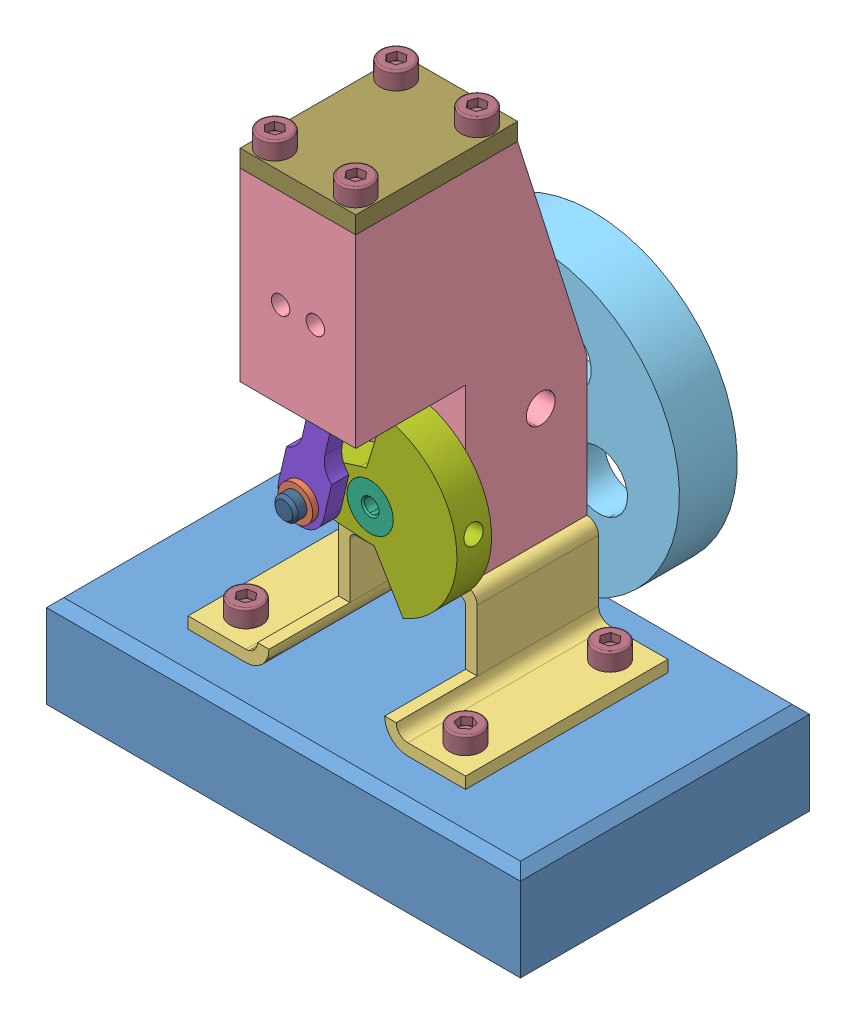
SolidWorks assembly airmotor, configuration Default. Lengths in mm.
Overall size (82 100.59 61).
20 component instances, 13 part files, 41 mates.
Components (placement in the parent):
- Part1-1: Part1 [Default] at (28.4885 33.8393 64.708) size (82 16 50)
- Part10-1: Part10 [Default] at (20.5462 75.4658 79.208) x (-1 0 0) z (0 -1 0) size (6 1 6)
- Part2-1: Part2 [Default] at (28.4885 33.5714 47.208) size (48 16.59 35)
- Part3-1: Part3 [Default] at (28.4885 66.4251 47.208) x (0 0 -1) z (1 0 0) size (40 62 20)
- Part4-1: Part4 [Default] at (28.4885 76.4251 46.208) x (0.91814 -0.396257 0) z (0.396257 0.91814 0) size (50 11 50)
- Part5-1: Part5 [Default] at (28.4885 76.4251 74.708) x (0 -1 0) z (1 0 0) size (8 46 8)
- Part6-1: Part6 [Default] at (28.4885 76.4251 71.708) x (0.11991 -0.992785 0) z (0 0 -1) size (28.91 27 6.5)
- Part7-1: Part7 [Default] at (22.9333 85.711 77.208) x (0.226922 0.973913 0) z (-0.973913 0.226922 0) size (42 3 8)
- Part8-1: Part8 [Default] at (28.4885 102.5527 77.208) x (-1 0 0) z (0 0 -1) size (14 15 14)
- Part9-1: Part9 [Default] at (19.7977 75.1346 75.208) x (0 0 -1) z (-0.40461 0.914489 0) size (13 4 4)
- Part11-1: Part11 [Default] at (28.4885 109.5527 83.958) x (-1 0 0) z (0 0 -1) size (3 3 13.5)
- Part12-1: Part12 [Default] at (28.4885 131.4251 73.208) x (0 0 1) z (1 0 0) size (28 3 20)
- socket head cap screw 4762_din-1: socket head cap screw 4762_din [EN ISO 4762 M3 x 6 - 6N] at (9.4885 54.8393 52.208) x (0 -1 0) z (-0.899893 0 0.43611) size (9 5.5 5.5)
- socket head cap screw 4762_din-2: socket head cap screw 4762_din [EN ISO 4762 M3 x 6 - 6N] at (9.4885 54.8393 77.208) x (0 -1 0) z (0.170896 0 0.985289) size (9 5.5 5.5)
- socket head cap screw 4762_din-3: socket head cap screw 4762_din [EN ISO 4762 M3 x 6 - 6N] at (47.4885 54.8393 77.208) x (0 -1 0) z (0.616405 0 0.787429) size (9 5.5 5.5)
- socket head cap screw 4762_din-4: socket head cap screw 4762_din [EN ISO 4762 M3 x 6 - 6N] at (47.4885 54.8393 52.208) x (0 -1 0) z (0.946527 0 0.322625) size (9 5.5 5.5)
- socket head cap screw 4762_din-5: socket head cap screw 4762_din [EN ISO 4762 M3 x 6 - 6N] at (21.4885 134.4251 84.208) x (0 -1 0) z (0.287137 0 0.95789) size (9 5.5 5.5)
- socket head cap screw 4762_din-6: socket head cap screw 4762_din [EN ISO 4762 M3 x 6 - 6N] at (35.4885 134.4251 63.208) x (0 -1 0) z (0.16771 0 0.985836) size (9 5.5 5.5)
- socket head cap screw 4762_din-7: socket head cap screw 4762_din [EN ISO 4762 M3 x 6 - 6N] at (35.4885 134.4251 84.208) x (0 -1 0) z (0.170795 0 0.985307) size (9 5.5 5.5)
- socket head cap screw 4762_din-8: socket head cap screw 4762_din [EN ISO 4762 M3 x 6 - 6N] at (21.4885 134.4251 63.208) x (0 -1 0) z (0.200162 0 0.979763) size (9 5.5 5.5)
Mates (geometry in assembly coordinates):
- Coincident1: coincident anti-aligned: plane of Part1-1 through (28.4885 49.8393 64.708) normal (0 1 0); plane of Part2-1 through (28.4885 49.8393 82.208) normal (0 -1 0)
- Concentric1: concentric aligned: cylinder of Part1-1 through (47.4885 49.8393 52.208) axis (0 1 0) radius 1.65; cylinder of Part2-1 through (47.4885 49.8393 52.208) axis (0 1 0) radius 2
- Concentric2: concentric aligned: cylinder of Part1-1 through (9.4885 49.8393 77.208) axis (0 1 0) radius 1.65; cylinder of Part2-1 through (9.4885 49.8393 77.208) axis (0 1 0) radius 2
- Coincident2: coincident anti-aligned: plane of Part2-1 through (28.4885 66.4251 68.208) normal (0 1 0); plane of Part3-1 through (38.4885 66.4251 47.208) normal (0 -1 0)
- Concentric3: concentric anti-aligned: cylinder of Part2-1 through (28.4885 49.8393 63.208) axis (0 1 0) radius 2; cylinder of Part3-1 through (28.4885 66.4251 63.208) axis (0 -1 0) radius 1.65
- Concentric4: concentric anti-aligned: cylinder of Part2-1 through (28.4885 49.8393 55.208) axis (0 1 0) radius 2; cylinder of Part3-1 through (28.4885 66.4251 55.208) axis (0 -1 0) radius 1.65
- Concentric5: concentric anti-aligned: cylinder of Part3-1 through (28.4885 77.4251 63.208) axis (0 1 0) radius 1; cylinder of Part5-1 through (28.4885 88.4251 63.208) axis (0 -1 0) radius 2
- Concentric6: concentric anti-aligned: cylinder of Part3-1 through (28.4885 76.4251 87.208) axis (0 0 -1) radius 4; cylinder of Part5-1 through (28.4885 76.4251 40.708) axis (0 0 1) radius 4
- Concentric7: concentric aligned: cylinder of Part4-1 through (28.4885 76.4251 36.208) axis (0 0 1) radius 4; cylinder of Part5-1 through (28.4885 76.4251 28.708) axis (0 0 1) radius 2
- Coincident3: coincident anti-aligned: plane of Part3-1 through (38.4885 90.4251 47.208) normal (0 0 -1); plane of Part4-1 through (28.4885 76.4251 47.208) normal (0 0 1)
- Concentric9: concentric anti-aligned: cylinder of Part8-1 through (28.4885 109.5527 84.208) axis (0 0 -1) radius 1.5; cylinder of Part11-1 through (28.4885 109.5527 70.458) axis (0 0 1) radius 1.5
- Concentric10: concentric aligned: cylinder of Part7-1 through (28.4885 109.5527 75.708) axis (0 0 1) radius 1.5; cylinder of Part11-1 through (28.4885 109.5527 70.458) axis (0 0 1) radius 1.5
- Concentric11: concentric anti-aligned: cylinder of Part6-1 through (20.5462 75.4658 68.708) axis (0 0 1) radius 2; cylinder of Part9-1 through (20.5462 75.4658 68.708) axis (0 0 -1) radius 2
- Concentric12: concentric anti-aligned: cylinder of Part10-1 through (20.5462 75.4658 78.708) axis (0 0 1) radius 1.9; cylinder of Part9-1 through (20.5462 75.4658 68.708) axis (0 0 -1) radius 1.6434
- Coincident4: coincident anti-aligned: plane of Part10-1 through (20.5462 75.4658 78.708) normal (0 0 -1); plane of Part9-1 through (19.0434 74.8009 78.708) normal (0 0 1)
- Concentric13: concentric anti-aligned: cylinder of Part7-1 through (20.5462 75.4658 75.708) axis (0 0 1) radius 2; cylinder of Part9-1 through (20.5462 75.4658 68.708) axis (0 0 -1) radius 2
- Concentric14: concentric aligned: cylinder of Part3-1 through (28.4885 66.4251 77.208) axis (0 1 0) radius 7; cylinder of Part8-1 through (28.4885 121.9198 77.208) axis (0 1 0) radius 7
- Width1: width anti-aligned: plane of Part11-1 through (28.4885 109.5527 70.458) normal (0 0 -1); plane of Part7-1 through (28.4885 109.5527 83.958) normal (0 0 1); plane of Part11-1 through (20.5462 75.4658 78.708) normal (0 0 1); plane of Part7-1 through (20.5462 75.4658 75.708) normal (0 0 -1)
- Concentric15: concentric aligned: cylinder of Part5-1 through (28.4885 76.4251 40.708) axis (0 0 1) radius 4; cylinder of Part6-1 through (28.4885 76.4251 68.208) axis (0 0 1) radius 4
- Coincident5: coincident aligned: plane of Part6-1 through (28.4885 76.4251 68.708) normal (0 0 -1); plane of Part9-1 through (20.5462 75.4658 68.708) normal (0 0 -1)
- Coincident6: coincident anti-aligned: plane of Part3-1 through (38.4885 66.4251 68.208) normal (0 0 1); plane of Part6-1 through (28.4885 76.4251 68.208) normal (0 0 -1)
- Coincident7: coincident anti-aligned: plane of Part10-1 through (20.5462 75.4658 78.708) normal (0 0 -1); plane of Part7-1 through (20.5462 75.4658 78.708) normal (0 0 1)
- Coincident9: coincident anti-aligned: plane of Part3-1 through (38.4885 128.4251 87.208) normal (0 1 0); plane of Part12-1 through (28.4885 128.4251 73.208) normal (0 -1 0)
- Coincident11: coincident aligned: plane of Part3-1 through (38.4885 96.4251 87.208) normal (0 0 1); plane of Part12-1 through (28.4885 128.4251 87.208) normal (0 0 1)
- Coincident12: coincident aligned: plane of Part3-1 through (18.4885 66.4251 47.208) normal (-1 0 0); plane of Part12-1 through (18.4885 128.4251 73.208) normal (-1 0 0)
- Concentric20: concentric aligned: cylinder of Part1-1 through (9.4885 49.8393 52.208) axis (0 1 0) radius 1.65; cylinder of socket head cap screw 4762_din-1 through (9.4885 86.5893 52.208) axis (0 1 0) radius 1.5
- Concentric21: concentric aligned: cylinder of Part1-1 through (9.4885 49.8393 77.208) axis (0 1 0) radius 1.65; cylinder of socket head cap screw 4762_din-2 through (9.4885 86.5893 77.208) axis (0 1 0) radius 1.5
- Concentric22: concentric aligned: cylinder of Part1-1 through (47.4885 49.8393 77.208) axis (0 1 0) radius 1.65; cylinder of socket head cap screw 4762_din-3 through (47.4885 86.5893 77.208) axis (0 1 0) radius 1.5
- Concentric23: concentric aligned: cylinder of Part1-1 through (47.4885 49.8393 52.208) axis (0 1 0) radius 1.65; cylinder of socket head cap screw 4762_din-4 through (47.4885 86.5893 52.208) axis (0 1 0) radius 1.5
- Coincident13: coincident anti-aligned: plane of Part2-1 through (28.4885 51.8393 82.208) normal (0 1 0); plane of socket head cap screw 4762_din-4 through (48.3757 51.8393 49.605) normal (0 -1 0)
- Coincident14: coincident anti-aligned: plane of Part2-1 through (28.4885 51.8393 82.208) normal (0 1 0); plane of socket head cap screw 4762_din-3 through (49.6539 51.8393 75.5129) normal (0 -1 0)
- Coincident15: coincident anti-aligned: plane of Part2-1 through (28.4885 51.8393 82.208) normal (0 1 0); plane of socket head cap screw 4762_din-2 through (12.198 51.8393 76.738) normal (0 -1 0)
- Coincident16: coincident anti-aligned: plane of Part2-1 through (28.4885 51.8393 82.208) normal (0 1 0); plane of socket head cap screw 4762_din-1 through (10.6878 51.8393 54.6827) normal (0 -1 0)
- Concentric24: concentric: cylinder of Part12-1 through (35.4885 131.4251 84.208) axis (0 1 0) radius 1.25; cylinder of socket head cap screw 4762_din-7 through (35.4885 166.1751 84.208) axis (0 1 0) radius 1.5
- Concentric25: concentric: cylinder of Part12-1 through (21.4885 131.4251 84.208) axis (0 1 0) radius 1.25; cylinder of socket head cap screw 4762_din-5 through (21.4885 166.1751 84.208) axis (0 1 0) radius 1.5
- Concentric26: concentric: cylinder of Part12-1 through (35.4885 131.4251 63.208) axis (0 1 0) radius 1.25; cylinder of socket head cap screw 4762_din-6 through (35.4885 166.1751 63.208) axis (0 1 0) radius 1.5
- Concentric27: concentric: cylinder of Part12-1 through (21.4885 131.4251 63.208) axis (0 1 0) radius 1.25; cylinder of socket head cap screw 4762_din-8 through (21.4885 166.1751 63.208) axis (0 1 0) radius 1.5
- Coincident17: coincident anti-aligned: plane of Part12-1 through (28.4885 131.4251 73.208) normal (0 1 0); plane of socket head cap screw 4762_din-7 through (38.1981 131.4251 83.7383) normal (0 -1 0)
- Coincident18: coincident anti-aligned: plane of Part12-1 through (28.4885 131.4251 73.208) normal (0 1 0); plane of socket head cap screw 4762_din-6 through (38.1995 131.4251 62.7468) normal (0 -1 0)
- Coincident19: coincident anti-aligned: plane of Part12-1 through (28.4885 131.4251 73.208) normal (0 1 0); plane of socket head cap screw 4762_din-8 through (24.1828 131.4251 62.6576) normal (0 -1 0)
- Coincident20: coincident anti-aligned: plane of Part12-1 through (28.4885 131.4251 73.208) normal (0 1 0); plane of socket head cap screw 4762_din-5 through (24.1227 131.4251 83.4184) normal (0 -1 0)
